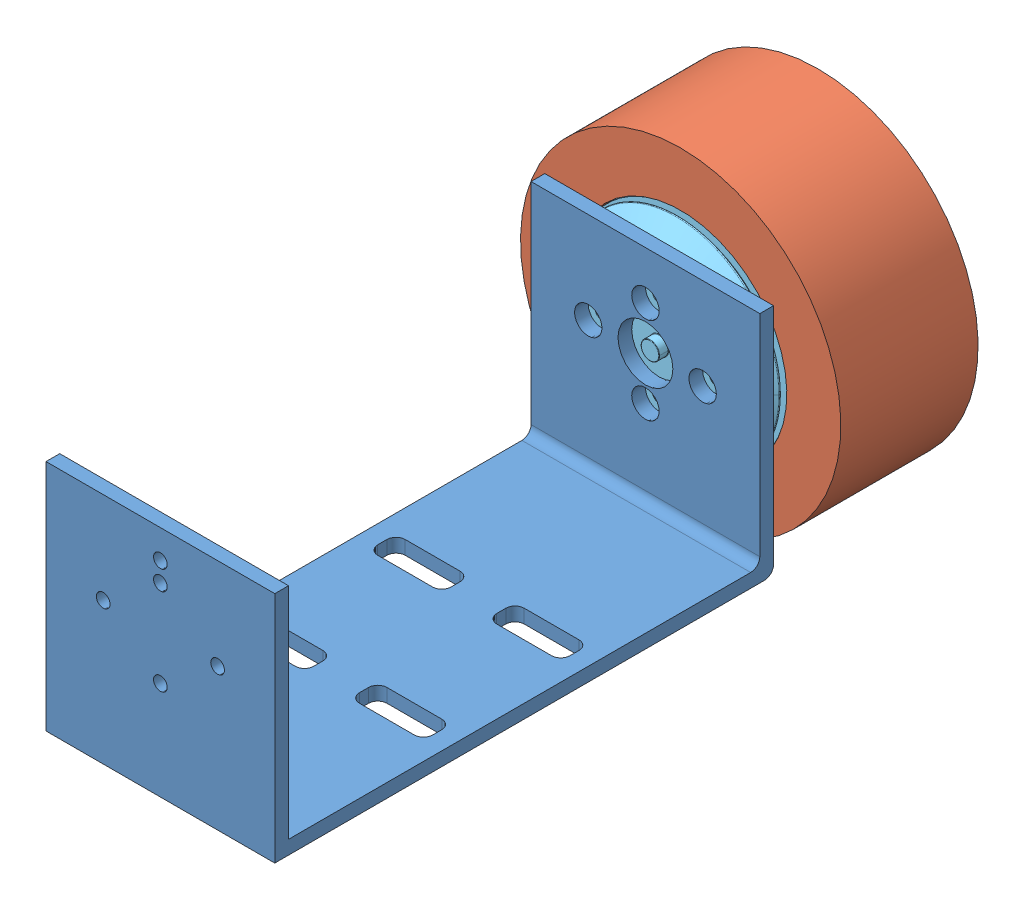
SolidWorks assembly 装配体5, configuration 默认. Lengths in mm.
Overall size (103.44 103.44 143.7).
8 component instances, 5 part files, 3 mates.
Components (placement in the parent):
- 电机固定支架-1: 电机固定支架 [默认] at (-4.8956 7.672 54.5) size (50 51 109)
- 电机+摩擦轮-1: 电机+摩擦轮 [默认] at (-50.2923 -38.8625 35.4251) x (0.706495 -0.707718 0) z (0.707718 0.706495 0) size (92.58 36.7 92.58)
  - 摩擦轮-1: 摩擦轮 [默认] at (-0.8607 -14.3749 65.0044) x (-0.410815 0 -0.911719) z (0.911719 0 -0.410815) size (70 30 70)
  - 4114电机-1: 4114电机 [默认] at (30.7352 -1.3863 98.4607) x (-0.707718 0 0.706495) z (-0.706495 0 -0.707718) size (46 36.7 46)
    - 4114电机.STEP-1: 4114电机.STEP [默认] at origin size (46 36.7 46)
      - ____3.STEP-1: ____3.STEP [默认] at (-1.2757 -9.9886 46) size (46 16 46)
      - ____2.STEP-1: ____2.STEP [默认] at (-1.2757 15.0114 46) size (46 11 46)
      - ____1.STEP-1: ____1.STEP [默认] at (-1.2757 -17.6886 46) x (-1 0 0) z (0 0 1) size (46 9.7 46)
Mates (geometry in assembly coordinates):
- 同心1: concentric aligned: cylinder of 电机固定支架-1 through (-4.8956 7.672 57.5) axis (0 0 -1) radius 6; cylinder of 电机+摩擦轮-1/4114电机-1/4114电机.STEP-1/____1.STEP-1 through (-4.8956 7.672 56.5) axis (0 0 -1) radius 2
- 同心4: concentric aligned: circle of 电机固定支架-1; circle of 电机+摩擦轮-1/4114电机-1/4114电机.STEP-1/____1.STEP-1
- 重合2: coincident anti-aligned: plane of 电机固定支架-1 through (-4.8956 7.672 54.5) normal (0 0 -1); plane of 电机+摩擦轮-1/4114电机-1/4114电机.STEP-1/____1.STEP-1 through (-4.8956 7.672 54.5) normal (0 0 1)
